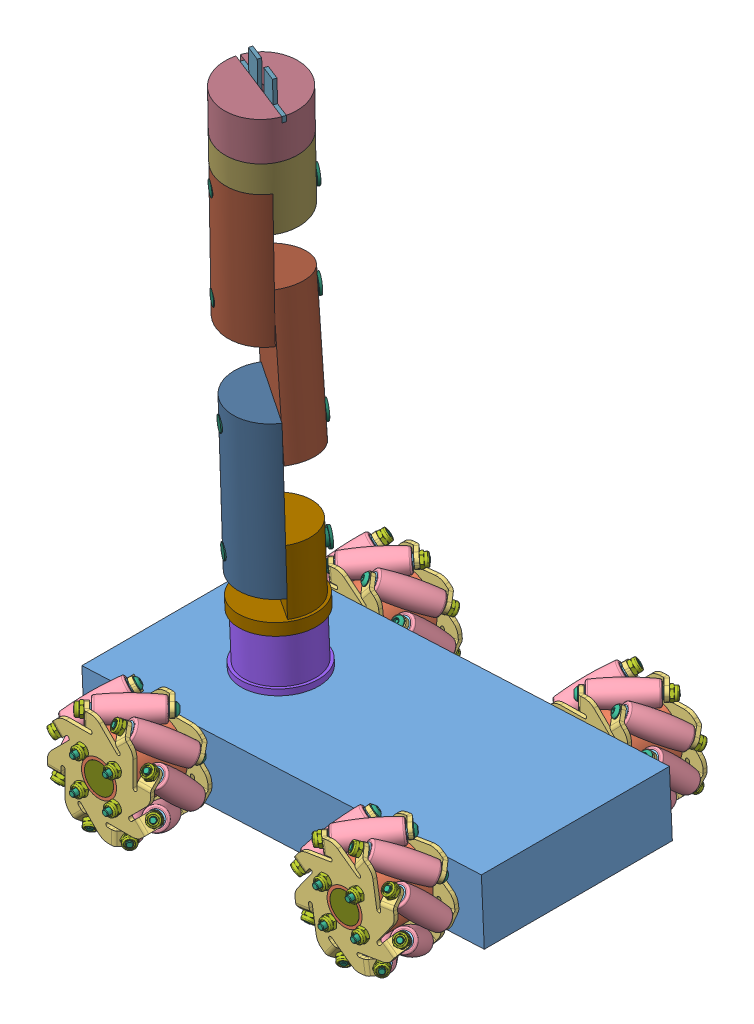
SolidWorks assembly bot assem, configuration Default. Lengths in mm.
Overall size (344.81 538.41 284.43).
226 component instances, 16 part files, 22 mates.
Components (placement in the parent):
- Part4-1: Part4 [Default] at (-50.0602 327.8462 218.6785) x (0.99893 0.046251 0) z (0 0 1) size (342.54 57 161.07)
- mecanum wheel assembly-2: mecanum wheel assembly [Default] at (-110.7954 326.5156 308.7657) size (102.2 102.2 64.43) (flexible)
  - 3.shaft-1: 3.shaft [Default] at (-45.6858 23.4322 30.452) size (53.34 53.34 52.51)
  - 1.frame-1: 1.frame [Default] at (-45.6858 23.4322 39.6232) x (-1 0 0) z (0 0 -1) size (91.71 91.71 12.64)
  - 1.frame-2: 1.frame [Default] at (-45.6858 23.4322 -6.2193) x (-1 0 0) z (0 0 1) size (91.71 91.71 12.64)
  - 2.roller-1: 2.roller [Default] at (-84.0268 23.5333 16.638) x (0 -0.707107 0.707107) z (0.983638 0.127391 0.127391) size (46.68 20 20)
  - 4.roller_bracket-1: 4.roller_bracket [Default] at (-84.0268 39.7299 0.4414) x (-0.383049 0.653174 0.653174) z (-0.923728 -0.270857 -0.270857) size (12.5 3.33 12.5)
  - 4.roller_bracket-2: 4.roller_bracket [Default] at (-84.0268 7.3367 32.8346) x (0.850043 -0.372442 -0.372442) z (-0.526713 -0.601071 -0.601071) size (12.5 3.33 12.5)
  - 5.bolt-2: 5.bolt [Default] at (-84.0268 36.2864 3.8849) x (0 -0.707107 0.707107) z (-0.604734 0.56316 0.56316) size (64.43 9.5 9.5)
  - torque nut 08_iso-1: torque nut 08_iso [ISO 10511-M6-N] at (-84.0268 1.8311 38.2658) x (1 0 0) z (0 -0.707107 0.707107) size (10 11.55 6)
  - 4.roller_bracket-3: 4.roller_bracket [Default] at (-84.3212 7.8452 0.4414) x (-0.732721 0.191007 0.653174) z (-0.46165 -0.844699 -0.270857) size (12.5 3.33 12.5)
  - 4.roller_bracket-4: 4.roller_bracket [Default] at (-61.9835 -14.9088 0.4414) x (-0.653174 -0.383049 0.653174) z (0.270857 -0.923728 -0.270857) size (12.5 3.33 12.5)
  - 4.roller_bracket-5: 4.roller_bracket [Default] at (-30.0988 -15.2032 0.4414) x (-0.191007 -0.732721 0.653174) z (0.844699 -0.46165 -0.270857) size (12.5 3.33 12.5)
  - 4.roller_bracket-6: 4.roller_bracket [Default] at (-7.3448 7.1345 0.4414) x (0.383049 -0.653174 0.653174) z (0.923728 0.270857 -0.270857) size (12.5 3.33 12.5)
  - 4.roller_bracket-7: 4.roller_bracket [Default] at (-7.0504 39.0192 0.4414) x (0.732721 -0.191007 0.653174) z (0.46165 0.844699 -0.270857) size (12.5 3.33 12.5)
  - 4.roller_bracket-8: 4.roller_bracket [Default] at (-29.3881 61.7732 0.4414) x (0.653174 0.383049 0.653174) z (-0.270857 0.923728 -0.270857) size (12.5 3.33 12.5)
  - 4.roller_bracket-9: 4.roller_bracket [Default] at (-61.2728 62.0676 0.4414) x (0.191007 0.732721 0.653174) z (-0.844699 0.46165 -0.270857) size (12.5 3.33 12.5)
  - 2.roller-2: 2.roller [Default] at (-72.8685 -3.6075 16.638) x (0.5 -0.5 0.707107) z (0.605458 0.785616 0.127391) size (46.68 20 20)
  - 2.roller-3: 2.roller [Default] at (-45.7869 -14.9088 16.638) x (0.707107 0 0.707107) z (-0.127391 0.983638 0.127391) size (46.68 20 20)
  - 2.roller-4: 2.roller [Default] at (-18.6461 -3.7505 16.638) x (0.5 0.5 0.707107) z (-0.785616 0.605458 0.127391) size (46.68 20 20)
  - 2.roller-5: 2.roller [Default] at (-7.3448 23.3311 16.638) x (0 0.707107 0.707107) z (-0.983638 -0.127391 0.127391) size (46.68 20 20)
  - 2.roller-6: 2.roller [Default] at (-18.5031 50.4719 16.638) x (-0.5 0.5 0.707107) z (-0.605458 -0.785616 0.127391) size (46.68 20 20)
  - 2.roller-7: 2.roller [Default] at (-45.5847 61.7732 16.638) x (-0.707107 0 0.707107) z (0.127391 -0.983638 0.127391) size (46.68 20 20)
  - 2.roller-8: 2.roller [Default] at (-72.7255 50.6149 16.638) x (-0.5 -0.5 0.707107) z (0.785616 -0.605458 0.127391) size (46.68 20 20)
  - 4.roller_bracket-10: 4.roller_bracket [Default] at (-61.4158 -15.0602 32.8346) x (0.864428 0.337715 -0.372442) z (0.052579 -0.797464 -0.601071) size (12.5 3.33 12.5)
  - 4.roller_bracket-11: 4.roller_bracket [Default] at (-29.5903 -14.9088 32.8346) x (0.372442 0.850043 -0.372442) z (0.601071 -0.526713 -0.601071) size (12.5 3.33 12.5)
  - 4.roller_bracket-12: 4.roller_bracket [Default] at (-7.1934 7.7022 32.8346) x (-0.337715 0.864428 -0.372442) z (0.797464 0.052579 -0.601071) size (12.5 3.33 12.5)
  - 4.roller_bracket-13: 4.roller_bracket [Default] at (-7.3448 39.5276 32.8346) x (-0.850043 0.372442 -0.372442) z (0.526713 0.601071 -0.601071) size (12.5 3.33 12.5)
  - 4.roller_bracket-14: 4.roller_bracket [Default] at (-29.9558 61.9246 32.8346) x (-0.864428 -0.337715 -0.372442) z (-0.052579 0.797464 -0.601071) size (12.5 3.33 12.5)
  - 4.roller_bracket-15: 4.roller_bracket [Default] at (-61.7812 61.7732 32.8346) x (-0.372442 -0.850043 -0.372442) z (-0.601071 0.526713 -0.601071) size (12.5 3.33 12.5)
  - 4.roller_bracket-16: 4.roller_bracket [Default] at (-84.1782 39.1622 32.8346) x (0.337715 -0.864428 -0.372442) z (-0.797464 -0.052579 -0.601071) size (12.5 3.33 12.5)
  - 5.bolt-3: 5.bolt [Default] at (-81.8863 5.4103 3.8849) x (0.5 -0.5 0.707107) z (-0.825825 -0.029397 0.56316) size (64.43 9.5 9.5)
  - 5.bolt-4: 5.bolt [Default] at (-58.54 -14.9088 3.8849) x (0.707107 0 0.707107) z (-0.56316 -0.604734 0.56316) size (64.43 9.5 9.5)
  - 5.bolt-5: 5.bolt [Default] at (-27.6639 -12.7683 3.8849) x (0.5 0.5 0.707107) z (0.029397 -0.825825 0.56316) size (64.43 9.5 9.5)
  - 5.bolt-6: 5.bolt [Default] at (-7.3448 10.578 3.8849) x (0 0.707107 0.707107) z (0.604734 -0.56316 0.56316) size (64.43 9.5 9.5)
  - 5.bolt-7: 5.bolt [Default] at (-9.4853 41.4541 3.8849) x (-0.5 0.5 0.707107) z (0.825825 0.029397 0.56316) size (64.43 9.5 9.5)
  - 5.bolt-8: 5.bolt [Default] at (-32.8316 61.7732 3.8849) x (-0.707107 0 0.707107) z (0.56316 0.604734 0.56316) size (64.43 9.5 9.5)
  - 5.bolt-9: 5.bolt [Default] at (-63.7077 59.6327 3.8849) x (-0.5 -0.5 0.707107) z (-0.029397 0.825825 0.56316) size (64.43 9.5 9.5)
  - torque nut 08_iso-2: torque nut 08_iso [ISO 10511-M6-N] at (-57.5227 -18.9532 38.2658) x (0.707107 0.707107 0) z (0.5 -0.5 0.707107) size (10 11.55 6)
  - torque nut 08_iso-3: torque nut 08_iso [ISO 10511-M6-N] at (-24.0847 -14.9088 38.2658) x (0 1 0) z (0.707107 0 0.707107) size (10 11.55 6)
  - torque nut 08_iso-4: torque nut 08_iso [ISO 10511-M6-N] at (-3.3004 11.5953 38.2658) x (-0.707107 0.707107 0) z (0.5 0.5 0.707107) size (10 11.55 6)
  - torque nut 08_iso-5: torque nut 08_iso [ISO 10511-M6-N] at (-7.3448 45.0332 38.2658) x (-1 0 0) z (0 0.707107 0.707107) size (10 11.55 6)
  - torque nut 08_iso-6: torque nut 08_iso [ISO 10511-M6-N] at (-33.8489 65.8176 38.2658) x (-0.707107 -0.707107 0) z (-0.5 0.5 0.707107) size (10 11.55 6)
  - torque nut 08_iso-7: torque nut 08_iso [ISO 10511-M6-N] at (-67.2868 61.7732 38.2658) x (0 -1 0) z (-0.707107 0 0.707107) size (10 11.55 6)
  - torque nut 08_iso-8: torque nut 08_iso [ISO 10511-M6-N] at (-88.0712 35.2691 38.2658) x (0.707107 -0.707107 0) z (-0.5 -0.5 0.707107) size (10 11.55 6)
  - 5.bolt-10: 5.bolt [Default] at (-31.5408 37.5772 -0.0834) x (0 0 1) z (-0.509821 0.86028 0) size (64.43 9.5 9.5)
  - torque nut 08_iso-9: torque nut 08_iso [ISO 10511-M6-N] at (-31.5408 37.5772 45.8572) x (0.993457 -0.114205 0) z (0 0 1) size (10 11.55 6)
  - 5.bolt-12: 5.bolt [Default] at (-59.8308 37.5772 -0.0834) x (0 0 1) z (-0.86028 -0.509821 0) size (64.43 9.5 9.5)
  - 5.bolt-13: 5.bolt [Default] at (-59.8308 9.2872 -0.0834) x (0 0 1) z (0.509821 -0.86028 0) size (64.43 9.5 9.5)
  - 5.bolt-14: 5.bolt [Default] at (-31.5408 9.2872 -0.0834) x (0 0 1) z (0.86028 0.509821 0) size (64.43 9.5 9.5)
  - torque nut 08_iso-11: torque nut 08_iso [ISO 10511-M6-N] at (-59.8308 37.5772 45.8572) x (0.114205 0.993457 0) z (0 0 1) size (10 11.55 6)
  - torque nut 08_iso-12: torque nut 08_iso [ISO 10511-M6-N] at (-59.8308 9.2872 45.8572) x (-0.993457 0.114205 0) z (0 0 1) size (10 11.55 6)
  - torque nut 08_iso-13: torque nut 08_iso [ISO 10511-M6-N] at (-31.5408 9.2872 45.8572) x (-0.114205 -0.993457 0) z (0 0 1) size (10 11.55 6)
- mecanum wheel assembly-3: mecanum wheel assembly [Default] at (102.6865 343.7947 308.7657) x (0.987351 0.158553 0) z (0 0 1) size (102.2 102.2 64.43) (flexible)
  - 3.shaft-1: 3.shaft [Default] at (-45.6858 23.4322 30.452) size (53.34 53.34 52.51)
  - 1.frame-1: 1.frame [Default] at (-45.6858 23.4322 39.6232) x (-1 0 0) z (0 0 -1) size (91.71 91.71 12.64)
  - 1.frame-2: 1.frame [Default] at (-45.6858 23.4322 -6.2193) x (-1 0 0) z (0 0 1) size (91.71 91.71 12.64)
  - 2.roller-1: 2.roller [Default] at (-84.0268 23.5333 16.638) x (0 -0.707107 0.707107) z (0.983638 0.127391 0.127391) size (46.68 20 20)
  - 4.roller_bracket-1: 4.roller_bracket [Default] at (-84.0268 39.7299 0.4414) x (-0.383049 0.653174 0.653174) z (-0.923728 -0.270857 -0.270857) size (12.5 3.33 12.5)
  - 4.roller_bracket-2: 4.roller_bracket [Default] at (-84.0268 7.3367 32.8346) x (0.850043 -0.372442 -0.372442) z (-0.526713 -0.601071 -0.601071) size (12.5 3.33 12.5)
  - 5.bolt-2: 5.bolt [Default] at (-84.0268 36.2864 3.8849) x (0 -0.707107 0.707107) z (-0.604734 0.56316 0.56316) size (64.43 9.5 9.5)
  - torque nut 08_iso-1: torque nut 08_iso [ISO 10511-M6-N] at (-84.0268 1.8311 38.2658) x (1 0 0) z (0 -0.707107 0.707107) size (10 11.55 6)
  - 4.roller_bracket-3: 4.roller_bracket [Default] at (-84.3212 7.8452 0.4414) x (-0.732721 0.191007 0.653174) z (-0.46165 -0.844699 -0.270857) size (12.5 3.33 12.5)
  - 4.roller_bracket-4: 4.roller_bracket [Default] at (-61.9835 -14.9088 0.4414) x (-0.653174 -0.383049 0.653174) z (0.270857 -0.923728 -0.270857) size (12.5 3.33 12.5)
  - 4.roller_bracket-5: 4.roller_bracket [Default] at (-30.0988 -15.2032 0.4414) x (-0.191007 -0.732721 0.653174) z (0.844699 -0.46165 -0.270857) size (12.5 3.33 12.5)
  - 4.roller_bracket-6: 4.roller_bracket [Default] at (-7.3448 7.1345 0.4414) x (0.383049 -0.653174 0.653174) z (0.923728 0.270857 -0.270857) size (12.5 3.33 12.5)
  - 4.roller_bracket-7: 4.roller_bracket [Default] at (-7.0504 39.0192 0.4414) x (0.732721 -0.191007 0.653174) z (0.46165 0.844699 -0.270857) size (12.5 3.33 12.5)
  - 4.roller_bracket-8: 4.roller_bracket [Default] at (-29.3881 61.7732 0.4414) x (0.653174 0.383049 0.653174) z (-0.270857 0.923728 -0.270857) size (12.5 3.33 12.5)
  - 4.roller_bracket-9: 4.roller_bracket [Default] at (-61.2728 62.0676 0.4414) x (0.191007 0.732721 0.653174) z (-0.844699 0.46165 -0.270857) size (12.5 3.33 12.5)
  - 2.roller-2: 2.roller [Default] at (-72.8685 -3.6075 16.638) x (0.5 -0.5 0.707107) z (0.605458 0.785616 0.127391) size (46.68 20 20)
  - 2.roller-3: 2.roller [Default] at (-45.7869 -14.9088 16.638) x (0.707107 0 0.707107) z (-0.127391 0.983638 0.127391) size (46.68 20 20)
  - 2.roller-4: 2.roller [Default] at (-18.6461 -3.7505 16.638) x (0.5 0.5 0.707107) z (-0.785616 0.605458 0.127391) size (46.68 20 20)
  - 2.roller-5: 2.roller [Default] at (-7.3448 23.3311 16.638) x (0 0.707107 0.707107) z (-0.983638 -0.127391 0.127391) size (46.68 20 20)
  - 2.roller-6: 2.roller [Default] at (-18.5031 50.4719 16.638) x (-0.5 0.5 0.707107) z (-0.605458 -0.785616 0.127391) size (46.68 20 20)
  - 2.roller-7: 2.roller [Default] at (-45.5847 61.7732 16.638) x (-0.707107 0 0.707107) z (0.127391 -0.983638 0.127391) size (46.68 20 20)
  - 2.roller-8: 2.roller [Default] at (-72.7255 50.6149 16.638) x (-0.5 -0.5 0.707107) z (0.785616 -0.605458 0.127391) size (46.68 20 20)
  - 4.roller_bracket-10: 4.roller_bracket [Default] at (-61.4158 -15.0602 32.8346) x (0.864428 0.337715 -0.372442) z (0.052579 -0.797464 -0.601071) size (12.5 3.33 12.5)
  - 4.roller_bracket-11: 4.roller_bracket [Default] at (-29.5903 -14.9088 32.8346) x (0.372442 0.850043 -0.372442) z (0.601071 -0.526713 -0.601071) size (12.5 3.33 12.5)
  - 4.roller_bracket-12: 4.roller_bracket [Default] at (-7.1934 7.7022 32.8346) x (-0.337715 0.864428 -0.372442) z (0.797464 0.052579 -0.601071) size (12.5 3.33 12.5)
  - 4.roller_bracket-13: 4.roller_bracket [Default] at (-7.3448 39.5276 32.8346) x (-0.850043 0.372442 -0.372442) z (0.526713 0.601071 -0.601071) size (12.5 3.33 12.5)
  - 4.roller_bracket-14: 4.roller_bracket [Default] at (-29.9558 61.9246 32.8346) x (-0.864428 -0.337715 -0.372442) z (-0.052579 0.797464 -0.601071) size (12.5 3.33 12.5)
  - 4.roller_bracket-15: 4.roller_bracket [Default] at (-61.7812 61.7732 32.8346) x (-0.372442 -0.850043 -0.372442) z (-0.601071 0.526713 -0.601071) size (12.5 3.33 12.5)
  - 4.roller_bracket-16: 4.roller_bracket [Default] at (-84.1782 39.1622 32.8346) x (0.337715 -0.864428 -0.372442) z (-0.797464 -0.052579 -0.601071) size (12.5 3.33 12.5)
  - 5.bolt-3: 5.bolt [Default] at (-81.8863 5.4103 3.8849) x (0.5 -0.5 0.707107) z (-0.825825 -0.029397 0.56316) size (64.43 9.5 9.5)
  - 5.bolt-4: 5.bolt [Default] at (-58.54 -14.9088 3.8849) x (0.707107 0 0.707107) z (-0.56316 -0.604734 0.56316) size (64.43 9.5 9.5)
  - 5.bolt-5: 5.bolt [Default] at (-27.6639 -12.7683 3.8849) x (0.5 0.5 0.707107) z (0.029397 -0.825825 0.56316) size (64.43 9.5 9.5)
  - 5.bolt-6: 5.bolt [Default] at (-7.3448 10.578 3.8849) x (0 0.707107 0.707107) z (0.604734 -0.56316 0.56316) size (64.43 9.5 9.5)
  - 5.bolt-7: 5.bolt [Default] at (-9.4853 41.4541 3.8849) x (-0.5 0.5 0.707107) z (0.825825 0.029397 0.56316) size (64.43 9.5 9.5)
  - 5.bolt-8: 5.bolt [Default] at (-32.8316 61.7732 3.8849) x (-0.707107 0 0.707107) z (0.56316 0.604734 0.56316) size (64.43 9.5 9.5)
  - 5.bolt-9: 5.bolt [Default] at (-63.7077 59.6327 3.8849) x (-0.5 -0.5 0.707107) z (-0.029397 0.825825 0.56316) size (64.43 9.5 9.5)
  - torque nut 08_iso-2: torque nut 08_iso [ISO 10511-M6-N] at (-57.5227 -18.9532 38.2658) x (0.707107 0.707107 0) z (0.5 -0.5 0.707107) size (10 11.55 6)
  - torque nut 08_iso-3: torque nut 08_iso [ISO 10511-M6-N] at (-24.0847 -14.9088 38.2658) x (0 1 0) z (0.707107 0 0.707107) size (10 11.55 6)
  - torque nut 08_iso-4: torque nut 08_iso [ISO 10511-M6-N] at (-3.3004 11.5953 38.2658) x (-0.707107 0.707107 0) z (0.5 0.5 0.707107) size (10 11.55 6)
  - torque nut 08_iso-5: torque nut 08_iso [ISO 10511-M6-N] at (-7.3448 45.0332 38.2658) x (-1 0 0) z (0 0.707107 0.707107) size (10 11.55 6)
  - torque nut 08_iso-6: torque nut 08_iso [ISO 10511-M6-N] at (-33.8489 65.8176 38.2658) x (-0.707107 -0.707107 0) z (-0.5 0.5 0.707107) size (10 11.55 6)
  - torque nut 08_iso-7: torque nut 08_iso [ISO 10511-M6-N] at (-67.2868 61.7732 38.2658) x (0 -1 0) z (-0.707107 0 0.707107) size (10 11.55 6)
  - torque nut 08_iso-8: torque nut 08_iso [ISO 10511-M6-N] at (-88.0712 35.2691 38.2658) x (0.707107 -0.707107 0) z (-0.5 -0.5 0.707107) size (10 11.55 6)
  - 5.bolt-10: 5.bolt [Default] at (-31.5408 37.5772 -0.0834) x (0 0 1) z (-0.509821 0.86028 0) size (64.43 9.5 9.5)
  - torque nut 08_iso-9: torque nut 08_iso [ISO 10511-M6-N] at (-31.5408 37.5772 45.8572) x (0.993457 -0.114205 0) z (0 0 1) size (10 11.55 6)
  - 5.bolt-12: 5.bolt [Default] at (-59.8308 37.5772 -0.0834) x (0 0 1) z (-0.86028 -0.509821 0) size (64.43 9.5 9.5)
  - 5.bolt-13: 5.bolt [Default] at (-59.8308 9.2872 -0.0834) x (0 0 1) z (0.509821 -0.86028 0) size (64.43 9.5 9.5)
  - 5.bolt-14: 5.bolt [Default] at (-31.5408 9.2872 -0.0834) x (0 0 1) z (0.86028 0.509821 0) size (64.43 9.5 9.5)
  - torque nut 08_iso-11: torque nut 08_iso [ISO 10511-M6-N] at (-59.8308 37.5772 45.8572) x (0.114205 0.993457 0) z (0 0 1) size (10 11.55 6)
  - torque nut 08_iso-12: torque nut 08_iso [ISO 10511-M6-N] at (-59.8308 9.2872 45.8572) x (-0.993457 0.114205 0) z (0 0 1) size (10 11.55 6)
  - torque nut 08_iso-13: torque nut 08_iso [ISO 10511-M6-N] at (-31.5408 9.2872 45.8572) x (-0.114205 -0.993457 0) z (0 0 1) size (10 11.55 6)
- mecanum wheel assembly-5: mecanum wheel assembly [Default] at (-113.5364 378.0903 128.5913) x (0.994367 0.105992 0) z (0 0 -1) size (102.2 102.2 64.43) (flexible)
  - 3.shaft-1: 3.shaft [Default] at (-45.6858 23.4322 30.452) size (53.34 53.34 52.51)
  - 1.frame-1: 1.frame [Default] at (-45.6858 23.4322 39.6232) x (-1 0 0) z (0 0 -1) size (91.71 91.71 12.64)
  - 1.frame-2: 1.frame [Default] at (-45.6858 23.4322 -6.2193) x (-1 0 0) z (0 0 1) size (91.71 91.71 12.64)
  - 2.roller-1: 2.roller [Default] at (-84.0268 23.5333 16.638) x (0 -0.707107 0.707107) z (0.983638 0.127391 0.127391) size (46.68 20 20)
  - 4.roller_bracket-1: 4.roller_bracket [Default] at (-84.0268 39.7299 0.4414) x (-0.383049 0.653174 0.653174) z (-0.923728 -0.270857 -0.270857) size (12.5 3.33 12.5)
  - 4.roller_bracket-2: 4.roller_bracket [Default] at (-84.0268 7.3367 32.8346) x (0.850043 -0.372442 -0.372442) z (-0.526713 -0.601071 -0.601071) size (12.5 3.33 12.5)
  - 5.bolt-2: 5.bolt [Default] at (-84.0268 36.2864 3.8849) x (0 -0.707107 0.707107) z (-0.604734 0.56316 0.56316) size (64.43 9.5 9.5)
  - torque nut 08_iso-1: torque nut 08_iso [ISO 10511-M6-N] at (-84.0268 1.8311 38.2658) x (1 0 0) z (0 -0.707107 0.707107) size (10 11.55 6)
  - 4.roller_bracket-3: 4.roller_bracket [Default] at (-84.3212 7.8452 0.4414) x (-0.732721 0.191007 0.653174) z (-0.46165 -0.844699 -0.270857) size (12.5 3.33 12.5)
  - 4.roller_bracket-4: 4.roller_bracket [Default] at (-61.9835 -14.9088 0.4414) x (-0.653174 -0.383049 0.653174) z (0.270857 -0.923728 -0.270857) size (12.5 3.33 12.5)
  - 4.roller_bracket-5: 4.roller_bracket [Default] at (-30.0988 -15.2032 0.4414) x (-0.191007 -0.732721 0.653174) z (0.844699 -0.46165 -0.270857) size (12.5 3.33 12.5)
  - 4.roller_bracket-6: 4.roller_bracket [Default] at (-7.3448 7.1345 0.4414) x (0.383049 -0.653174 0.653174) z (0.923728 0.270857 -0.270857) size (12.5 3.33 12.5)
  - 4.roller_bracket-7: 4.roller_bracket [Default] at (-7.0504 39.0192 0.4414) x (0.732721 -0.191007 0.653174) z (0.46165 0.844699 -0.270857) size (12.5 3.33 12.5)
  - 4.roller_bracket-8: 4.roller_bracket [Default] at (-29.3881 61.7732 0.4414) x (0.653174 0.383049 0.653174) z (-0.270857 0.923728 -0.270857) size (12.5 3.33 12.5)
  - 4.roller_bracket-9: 4.roller_bracket [Default] at (-61.2728 62.0676 0.4414) x (0.191007 0.732721 0.653174) z (-0.844699 0.46165 -0.270857) size (12.5 3.33 12.5)
  - 2.roller-2: 2.roller [Default] at (-72.8685 -3.6075 16.638) x (0.5 -0.5 0.707107) z (0.605458 0.785616 0.127391) size (46.68 20 20)
  - 2.roller-3: 2.roller [Default] at (-45.7869 -14.9088 16.638) x (0.707107 0 0.707107) z (-0.127391 0.983638 0.127391) size (46.68 20 20)
  - 2.roller-4: 2.roller [Default] at (-18.6461 -3.7505 16.638) x (0.5 0.5 0.707107) z (-0.785616 0.605458 0.127391) size (46.68 20 20)
  - 2.roller-5: 2.roller [Default] at (-7.3448 23.3311 16.638) x (0 0.707107 0.707107) z (-0.983638 -0.127391 0.127391) size (46.68 20 20)
  - 2.roller-6: 2.roller [Default] at (-18.5031 50.4719 16.638) x (-0.5 0.5 0.707107) z (-0.605458 -0.785616 0.127391) size (46.68 20 20)
  - 2.roller-7: 2.roller [Default] at (-45.5847 61.7732 16.638) x (-0.707107 0 0.707107) z (0.127391 -0.983638 0.127391) size (46.68 20 20)
  - 2.roller-8: 2.roller [Default] at (-72.7255 50.6149 16.638) x (-0.5 -0.5 0.707107) z (0.785616 -0.605458 0.127391) size (46.68 20 20)
  - 4.roller_bracket-10: 4.roller_bracket [Default] at (-61.4158 -15.0602 32.8346) x (0.864428 0.337715 -0.372442) z (0.052579 -0.797464 -0.601071) size (12.5 3.33 12.5)
  - 4.roller_bracket-11: 4.roller_bracket [Default] at (-29.5903 -14.9088 32.8346) x (0.372442 0.850043 -0.372442) z (0.601071 -0.526713 -0.601071) size (12.5 3.33 12.5)
  - 4.roller_bracket-12: 4.roller_bracket [Default] at (-7.1934 7.7022 32.8346) x (-0.337715 0.864428 -0.372442) z (0.797464 0.052579 -0.601071) size (12.5 3.33 12.5)
  - 4.roller_bracket-13: 4.roller_bracket [Default] at (-7.3448 39.5276 32.8346) x (-0.850043 0.372442 -0.372442) z (0.526713 0.601071 -0.601071) size (12.5 3.33 12.5)
  - 4.roller_bracket-14: 4.roller_bracket [Default] at (-29.9558 61.9246 32.8346) x (-0.864428 -0.337715 -0.372442) z (-0.052579 0.797464 -0.601071) size (12.5 3.33 12.5)
  - 4.roller_bracket-15: 4.roller_bracket [Default] at (-61.7812 61.7732 32.8346) x (-0.372442 -0.850043 -0.372442) z (-0.601071 0.526713 -0.601071) size (12.5 3.33 12.5)
  - 4.roller_bracket-16: 4.roller_bracket [Default] at (-84.1782 39.1622 32.8346) x (0.337715 -0.864428 -0.372442) z (-0.797464 -0.052579 -0.601071) size (12.5 3.33 12.5)
  - 5.bolt-3: 5.bolt [Default] at (-81.8863 5.4103 3.8849) x (0.5 -0.5 0.707107) z (-0.825825 -0.029397 0.56316) size (64.43 9.5 9.5)
  - 5.bolt-4: 5.bolt [Default] at (-58.54 -14.9088 3.8849) x (0.707107 0 0.707107) z (-0.56316 -0.604734 0.56316) size (64.43 9.5 9.5)
  - 5.bolt-5: 5.bolt [Default] at (-27.6639 -12.7683 3.8849) x (0.5 0.5 0.707107) z (0.029397 -0.825825 0.56316) size (64.43 9.5 9.5)
  - 5.bolt-6: 5.bolt [Default] at (-7.3448 10.578 3.8849) x (0 0.707107 0.707107) z (0.604734 -0.56316 0.56316) size (64.43 9.5 9.5)
  - 5.bolt-7: 5.bolt [Default] at (-9.4853 41.4541 3.8849) x (-0.5 0.5 0.707107) z (0.825825 0.029397 0.56316) size (64.43 9.5 9.5)
  - 5.bolt-8: 5.bolt [Default] at (-32.8316 61.7732 3.8849) x (-0.707107 0 0.707107) z (0.56316 0.604734 0.56316) size (64.43 9.5 9.5)
  - 5.bolt-9: 5.bolt [Default] at (-63.7077 59.6327 3.8849) x (-0.5 -0.5 0.707107) z (-0.029397 0.825825 0.56316) size (64.43 9.5 9.5)
  - torque nut 08_iso-2: torque nut 08_iso [ISO 10511-M6-N] at (-57.5227 -18.9532 38.2658) x (0.707107 0.707107 0) z (0.5 -0.5 0.707107) size (10 11.55 6)
  - torque nut 08_iso-3: torque nut 08_iso [ISO 10511-M6-N] at (-24.0847 -14.9088 38.2658) x (0 1 0) z (0.707107 0 0.707107) size (10 11.55 6)
  - torque nut 08_iso-4: torque nut 08_iso [ISO 10511-M6-N] at (-3.3004 11.5953 38.2658) x (-0.707107 0.707107 0) z (0.5 0.5 0.707107) size (10 11.55 6)
  - torque nut 08_iso-5: torque nut 08_iso [ISO 10511-M6-N] at (-7.3448 45.0332 38.2658) x (-1 0 0) z (0 0.707107 0.707107) size (10 11.55 6)
  - torque nut 08_iso-6: torque nut 08_iso [ISO 10511-M6-N] at (-33.8489 65.8176 38.2658) x (-0.707107 -0.707107 0) z (-0.5 0.5 0.707107) size (10 11.55 6)
  - torque nut 08_iso-7: torque nut 08_iso [ISO 10511-M6-N] at (-67.2868 61.7732 38.2658) x (0 -1 0) z (-0.707107 0 0.707107) size (10 11.55 6)
  - torque nut 08_iso-8: torque nut 08_iso [ISO 10511-M6-N] at (-88.0712 35.2691 38.2658) x (0.707107 -0.707107 0) z (-0.5 -0.5 0.707107) size (10 11.55 6)
  - 5.bolt-10: 5.bolt [Default] at (-31.5408 37.5772 -0.0834) x (0 0 1) z (-0.509821 0.86028 0) size (64.43 9.5 9.5)
  - torque nut 08_iso-9: torque nut 08_iso [ISO 10511-M6-N] at (-31.5408 37.5772 45.8572) x (0.993457 -0.114205 0) z (0 0 1) size (10 11.55 6)
  - 5.bolt-12: 5.bolt [Default] at (-59.8308 37.5772 -0.0834) x (0 0 1) z (-0.86028 -0.509821 0) size (64.43 9.5 9.5)
  - 5.bolt-13: 5.bolt [Default] at (-59.8308 9.2872 -0.0834) x (0 0 1) z (0.509821 -0.86028 0) size (64.43 9.5 9.5)
  - 5.bolt-14: 5.bolt [Default] at (-31.5408 9.2872 -0.0834) x (0 0 1) z (0.86028 0.509821 0) size (64.43 9.5 9.5)
  - torque nut 08_iso-11: torque nut 08_iso [ISO 10511-M6-N] at (-59.8308 37.5772 45.8572) x (0.114205 0.993457 0) z (0 0 1) size (10 11.55 6)
  - torque nut 08_iso-12: torque nut 08_iso [ISO 10511-M6-N] at (-59.8308 9.2872 45.8572) x (-0.993457 0.114205 0) z (0 0 1) size (10 11.55 6)
  - torque nut 08_iso-13: torque nut 08_iso [ISO 10511-M6-N] at (-31.5408 9.2872 45.8572) x (-0.114205 -0.993457 0) z (0 0 1) size (10 11.55 6)
- mecanum wheel assembly-7: mecanum wheel assembly [Default] at (99.2444 383.7039 128.5913) x (0.999918 0.012843 0) z (0 0 -1) size (102.2 102.2 64.43) (flexible)
  - 3.shaft-1: 3.shaft [Default] at (-45.6858 23.4322 30.452) size (53.34 53.34 52.51)
  - 1.frame-1: 1.frame [Default] at (-45.6858 23.4322 39.6232) x (-1 0 0) z (0 0 -1) size (91.71 91.71 12.64)
  - 1.frame-2: 1.frame [Default] at (-45.6858 23.4322 -6.2193) x (-1 0 0) z (0 0 1) size (91.71 91.71 12.64)
  - 2.roller-1: 2.roller [Default] at (-84.0268 23.5333 16.638) x (0 -0.707107 0.707107) z (0.983638 0.127391 0.127391) size (46.68 20 20)
  - 4.roller_bracket-1: 4.roller_bracket [Default] at (-84.0268 39.7299 0.4414) x (-0.383049 0.653174 0.653174) z (-0.923728 -0.270857 -0.270857) size (12.5 3.33 12.5)
  - 4.roller_bracket-2: 4.roller_bracket [Default] at (-84.0268 7.3367 32.8346) x (0.850043 -0.372442 -0.372442) z (-0.526713 -0.601071 -0.601071) size (12.5 3.33 12.5)
  - 5.bolt-2: 5.bolt [Default] at (-84.0268 36.2864 3.8849) x (0 -0.707107 0.707107) z (-0.604734 0.56316 0.56316) size (64.43 9.5 9.5)
  - torque nut 08_iso-1: torque nut 08_iso [ISO 10511-M6-N] at (-84.0268 1.8311 38.2658) x (1 0 0) z (0 -0.707107 0.707107) size (10 11.55 6)
  - 4.roller_bracket-3: 4.roller_bracket [Default] at (-84.3212 7.8452 0.4414) x (-0.732721 0.191007 0.653174) z (-0.46165 -0.844699 -0.270857) size (12.5 3.33 12.5)
  - 4.roller_bracket-4: 4.roller_bracket [Default] at (-61.9835 -14.9088 0.4414) x (-0.653174 -0.383049 0.653174) z (0.270857 -0.923728 -0.270857) size (12.5 3.33 12.5)
  - 4.roller_bracket-5: 4.roller_bracket [Default] at (-30.0988 -15.2032 0.4414) x (-0.191007 -0.732721 0.653174) z (0.844699 -0.46165 -0.270857) size (12.5 3.33 12.5)
  - 4.roller_bracket-6: 4.roller_bracket [Default] at (-7.3448 7.1345 0.4414) x (0.383049 -0.653174 0.653174) z (0.923728 0.270857 -0.270857) size (12.5 3.33 12.5)
  - 4.roller_bracket-7: 4.roller_bracket [Default] at (-7.0504 39.0192 0.4414) x (0.732721 -0.191007 0.653174) z (0.46165 0.844699 -0.270857) size (12.5 3.33 12.5)
  - 4.roller_bracket-8: 4.roller_bracket [Default] at (-29.3881 61.7732 0.4414) x (0.653174 0.383049 0.653174) z (-0.270857 0.923728 -0.270857) size (12.5 3.33 12.5)
  - 4.roller_bracket-9: 4.roller_bracket [Default] at (-61.2728 62.0676 0.4414) x (0.191007 0.732721 0.653174) z (-0.844699 0.46165 -0.270857) size (12.5 3.33 12.5)
  - 2.roller-2: 2.roller [Default] at (-72.8685 -3.6075 16.638) x (0.5 -0.5 0.707107) z (0.605458 0.785616 0.127391) size (46.68 20 20)
  - 2.roller-3: 2.roller [Default] at (-45.7869 -14.9088 16.638) x (0.707107 0 0.707107) z (-0.127391 0.983638 0.127391) size (46.68 20 20)
  - 2.roller-4: 2.roller [Default] at (-18.6461 -3.7505 16.638) x (0.5 0.5 0.707107) z (-0.785616 0.605458 0.127391) size (46.68 20 20)
  - 2.roller-5: 2.roller [Default] at (-7.3448 23.3311 16.638) x (0 0.707107 0.707107) z (-0.983638 -0.127391 0.127391) size (46.68 20 20)
  - 2.roller-6: 2.roller [Default] at (-18.5031 50.4719 16.638) x (-0.5 0.5 0.707107) z (-0.605458 -0.785616 0.127391) size (46.68 20 20)
  - 2.roller-7: 2.roller [Default] at (-45.5847 61.7732 16.638) x (-0.707107 0 0.707107) z (0.127391 -0.983638 0.127391) size (46.68 20 20)
  - 2.roller-8: 2.roller [Default] at (-72.7255 50.6149 16.638) x (-0.5 -0.5 0.707107) z (0.785616 -0.605458 0.127391) size (46.68 20 20)
  - 4.roller_bracket-10: 4.roller_bracket [Default] at (-61.4158 -15.0602 32.8346) x (0.864428 0.337715 -0.372442) z (0.052579 -0.797464 -0.601071) size (12.5 3.33 12.5)
  - 4.roller_bracket-11: 4.roller_bracket [Default] at (-29.5903 -14.9088 32.8346) x (0.372442 0.850043 -0.372442) z (0.601071 -0.526713 -0.601071) size (12.5 3.33 12.5)
  - 4.roller_bracket-12: 4.roller_bracket [Default] at (-7.1934 7.7022 32.8346) x (-0.337715 0.864428 -0.372442) z (0.797464 0.052579 -0.601071) size (12.5 3.33 12.5)
  - 4.roller_bracket-13: 4.roller_bracket [Default] at (-7.3448 39.5276 32.8346) x (-0.850043 0.372442 -0.372442) z (0.526713 0.601071 -0.601071) size (12.5 3.33 12.5)
  - 4.roller_bracket-14: 4.roller_bracket [Default] at (-29.9558 61.9246 32.8346) x (-0.864428 -0.337715 -0.372442) z (-0.052579 0.797464 -0.601071) size (12.5 3.33 12.5)
  - 4.roller_bracket-15: 4.roller_bracket [Default] at (-61.7812 61.7732 32.8346) x (-0.372442 -0.850043 -0.372442) z (-0.601071 0.526713 -0.601071) size (12.5 3.33 12.5)
  - 4.roller_bracket-16: 4.roller_bracket [Default] at (-84.1782 39.1622 32.8346) x (0.337715 -0.864428 -0.372442) z (-0.797464 -0.052579 -0.601071) size (12.5 3.33 12.5)
  - 5.bolt-3: 5.bolt [Default] at (-81.8863 5.4103 3.8849) x (0.5 -0.5 0.707107) z (-0.825825 -0.029397 0.56316) size (64.43 9.5 9.5)
  - 5.bolt-4: 5.bolt [Default] at (-58.54 -14.9088 3.8849) x (0.707107 0 0.707107) z (-0.56316 -0.604734 0.56316) size (64.43 9.5 9.5)
  - 5.bolt-5: 5.bolt [Default] at (-27.6639 -12.7683 3.8849) x (0.5 0.5 0.707107) z (0.029397 -0.825825 0.56316) size (64.43 9.5 9.5)
  - 5.bolt-6: 5.bolt [Default] at (-7.3448 10.578 3.8849) x (0 0.707107 0.707107) z (0.604734 -0.56316 0.56316) size (64.43 9.5 9.5)
  - 5.bolt-7: 5.bolt [Default] at (-9.4853 41.4541 3.8849) x (-0.5 0.5 0.707107) z (0.825825 0.029397 0.56316) size (64.43 9.5 9.5)
  - 5.bolt-8: 5.bolt [Default] at (-32.8316 61.7732 3.8849) x (-0.707107 0 0.707107) z (0.56316 0.604734 0.56316) size (64.43 9.5 9.5)
  - 5.bolt-9: 5.bolt [Default] at (-63.7077 59.6327 3.8849) x (-0.5 -0.5 0.707107) z (-0.029397 0.825825 0.56316) size (64.43 9.5 9.5)
  - torque nut 08_iso-2: torque nut 08_iso [ISO 10511-M6-N] at (-57.5227 -18.9532 38.2658) x (0.707107 0.707107 0) z (0.5 -0.5 0.707107) size (10 11.55 6)
  - torque nut 08_iso-3: torque nut 08_iso [ISO 10511-M6-N] at (-24.0847 -14.9088 38.2658) x (0 1 0) z (0.707107 0 0.707107) size (10 11.55 6)
  - torque nut 08_iso-4: torque nut 08_iso [ISO 10511-M6-N] at (-3.3004 11.5953 38.2658) x (-0.707107 0.707107 0) z (0.5 0.5 0.707107) size (10 11.55 6)
  - torque nut 08_iso-5: torque nut 08_iso [ISO 10511-M6-N] at (-7.3448 45.0332 38.2658) x (-1 0 0) z (0 0.707107 0.707107) size (10 11.55 6)
  - torque nut 08_iso-6: torque nut 08_iso [ISO 10511-M6-N] at (-33.8489 65.8176 38.2658) x (-0.707107 -0.707107 0) z (-0.5 0.5 0.707107) size (10 11.55 6)
  - torque nut 08_iso-7: torque nut 08_iso [ISO 10511-M6-N] at (-67.2868 61.7732 38.2658) x (0 -1 0) z (-0.707107 0 0.707107) size (10 11.55 6)
  - torque nut 08_iso-8: torque nut 08_iso [ISO 10511-M6-N] at (-88.0712 35.2691 38.2658) x (0.707107 -0.707107 0) z (-0.5 -0.5 0.707107) size (10 11.55 6)
  - 5.bolt-10: 5.bolt [Default] at (-31.5408 37.5772 -0.0834) x (0 0 1) z (-0.509821 0.86028 0) size (64.43 9.5 9.5)
  - torque nut 08_iso-9: torque nut 08_iso [ISO 10511-M6-N] at (-31.5408 37.5772 45.8572) x (0.993457 -0.114205 0) z (0 0 1) size (10 11.55 6)
  - 5.bolt-12: 5.bolt [Default] at (-59.8308 37.5772 -0.0834) x (0 0 1) z (-0.86028 -0.509821 0) size (64.43 9.5 9.5)
  - 5.bolt-13: 5.bolt [Default] at (-59.8308 9.2872 -0.0834) x (0 0 1) z (0.509821 -0.86028 0) size (64.43 9.5 9.5)
  - 5.bolt-14: 5.bolt [Default] at (-31.5408 9.2872 -0.0834) x (0 0 1) z (0.86028 0.509821 0) size (64.43 9.5 9.5)
  - torque nut 08_iso-11: torque nut 08_iso [ISO 10511-M6-N] at (-59.8308 37.5772 45.8572) x (0.114205 0.993457 0) z (0 0 1) size (10 11.55 6)
  - torque nut 08_iso-12: torque nut 08_iso [ISO 10511-M6-N] at (-59.8308 9.2872 45.8572) x (-0.993457 0.114205 0) z (0 0 1) size (10 11.55 6)
  - torque nut 08_iso-13: torque nut 08_iso [ISO 10511-M6-N] at (-31.5408 9.2872 45.8572) x (-0.114205 -0.993457 0) z (0 0 1) size (10 11.55 6)
- arm assem-2: arm assem [Default] at (-164.0861 361.5635 189.6567) x (0.99893 0.046251 0) z (0 0 1) size (102.36 450.82 98.34) (flexible)
  - 1.base-1: 1.base [Default] at (31.0727 15.045 29.0218) x (-1 0 0) z (0 0 1) size (65 43.19 65)
  - link1-2: link1 [Default] at (31.0727 58.235 29.0218) x (-0.830749 0 -0.556647) z (-0.556647 0 0.830749) size (65 65.59 65)
  - link 2-3: link 2 [Default] at (30.3905 85.8409 28.5646) x (-0.556647 0 0.830749) z (0.829884 -0.045625 0.556067) size (32.5 131.37 65)
  - link 3-3: link 3 [Default] at (24.4867 299.7261 24.6088) x (-0.556647 0 0.830749) z (-0.824633 -0.121126 -0.552548) size (32.5 119.38 65)
  - link 3-4: link 3 [Default] at (34.7812 384.7834 31.5066) x (0.556647 0 -0.830749) z (0.82631 -0.103245 0.553672) size (32.5 119.38 65)
  - link4-4: link4 [Default] at (36.8397 408.6551 32.8859) x (-0.82631 0.103245 -0.553672) z (-0.556647 0 0.830749) size (65 57.79 65)
  - gripper assem-1: gripper assem [Default] at (-2.666 419.7032 33.2245) x (-0.937026 0.100134 -0.334598) z (0.338564 0.025153 -0.940607) size (65 54.79 65) (flexible)
    - gripper head-1: gripper head [Default] at (-38.0108 -7.62 13.4158) size (65 34.79 65)
    - gripper jaw-1: gripper jaw [Default] at (-57.98 22.173 13.4158) size (25 25 3)
    - gripper jaw-2: gripper jaw [Default] at (-23.7863 22.173 13.4158) x (-1 0 0) z (0 0 -1) size (25 25 3)
- bolt-1: bolt [Default] at (-118.9428 467.5871 190.433) x (-0.556051 -0.025745 0.830749) z (0.831111 -0.00782 0.556051) size (67 15 15)
- bolt-2: bolt [Default] at (-119.7382 562.9267 192.8553) x (-0.556051 -0.025745 0.830749) z (0.830177 0.031093 0.556632) size (67 15 15)
- bolt-4: bolt [Default] at (-131.9771 647.3035 186.6763) x (-0.556051 -0.025745 0.830749) z (0.828614 0.060828 0.556507) size (67 15 15)
- bolt-6: bolt [Default] at (-128.5856 732.5768 191.5891) x (-0.556051 -0.025745 0.830749) z (0.827167 0.080573 0.55615) size (67 15 15)
- axle-2: axle [Default] at (53.8633 359.6868 351.7341) x (0 0 -1) z (1 0 0) size (266.1 25 25)
- axle-3: axle [Default] at (-156.4812 349.9478 351.7341) x (0 0 -1) z (0.987351 0.158553 0) size (266.1 25 25)
Mates (geometry in assembly coordinates):
- Concentric1: concentric anti-aligned: cylinder of Part4-1 through (-156.4812 349.9478 478.1646) axis (0 0 -1) radius 9; cylinder of mecanum wheel assembly-2/3.shaft-1 through (-156.4812 349.9478 302.5464) axis (0 0 1) radius 12.5025
- Coincident1: coincident anti-aligned: plane of Part4-1 through (-223.6462 373.8669 299.2124) normal (0 0 1); plane of mecanum wheel assembly-2/3.shaft-1 through (-156.4812 349.9478 299.2124) normal (0 0 -1)
- Concentric2: concentric anti-aligned: cylinder of Part4-1 through (53.8633 359.6868 478.1646) axis (0 0 -1) radius 9; cylinder of mecanum wheel assembly-3/3.shaft-1 through (53.8633 359.6868 302.5464) axis (0 0 1) radius 12.5025
- Coincident2: coincident anti-aligned: plane of Part4-1 through (-223.6462 373.8669 299.2124) normal (0 0 1); plane of mecanum wheel assembly-3/3.shaft-1 through (53.8633 359.6868 299.2124) normal (0 0 -1)
- Concentric3: concentric aligned: cylinder of Part4-1 through (-156.4812 349.9478 478.1646) axis (0 0 -1) radius 9; cylinder of mecanum wheel assembly-5/3.shaft-1 through (-156.4812 349.9478 134.8106) axis (0 0 -1) radius 12.5025
- Coincident3: coincident anti-aligned: plane of Part4-1 through (-223.6462 373.8669 138.1446) normal (0 0 -1); plane of mecanum wheel assembly-5/3.shaft-1 through (-156.4812 349.9478 138.1446) normal (0 0 1)
- Concentric4: concentric aligned: cylinder of Part4-1 through (53.8633 359.6868 478.1646) axis (0 0 -1) radius 9; cylinder of mecanum wheel assembly-7/3.shaft-1 through (53.8633 359.6868 134.8106) axis (0 0 -1) radius 12.5025
- Coincident4: coincident anti-aligned: plane of Part4-1 through (-223.6462 373.8669 138.1446) normal (0 0 -1); plane of mecanum wheel assembly-7/3.shaft-1 through (53.8633 359.6868 138.1446) normal (0 0 1)
- Concentric6: concentric anti-aligned: circle of Part4-1; circle of arm assem-2/1.base-1
- Coincident6: coincident anti-aligned: plane of Part4-1 through (-52.5577 381.7884 218.6785) normal (-0.046251 0.99893 0); plane of arm assem-2/1.base-1 through (-133.7425 378.0295 218.6785) normal (0.046251 -0.99893 0)
- Concentric7: concentric anti-aligned: cylinder of arm assem-2/link1-2 through (-112.8262 467.8703 181.2948) axis (-0.556051 -0.025745 0.830749) radius 6; cylinder of bolt-1 through (-156.1982 465.8621 246.0932) axis (0.556051 0.025745 -0.830749) radius 6
- Distance1: distance = 32 mm: plane of bolt-1 through (-120.0549 467.5356 192.0945) normal (-0.556051 -0.025745 0.830749); cylinder of arm assem-2/link1-2 through (-138.681 484.6925 218.6785) axis (0.046251 -0.99893 0) radius 30
- Concentric8: concentric anti-aligned: cylinder of arm assem-2/link 3-3 through (-107.5051 563.4931 174.5788) axis (-0.556051 -0.025745 0.830749) radius 6; cylinder of bolt-2 through (-156.9936 561.2017 248.5155) axis (0.556051 0.025745 -0.830749) radius 6
- Distance2: distance = 32 mm: plane of bolt-2 through (-120.8503 562.8752 194.5168) normal (-0.556051 -0.025745 0.830749); cylinder of arm assem-2/link 3-3 through (-136.0082 544.2868 222.3144) axis (-0.146428 0.986921 -0.067424) radius 32.5
- Concentric9: concentric anti-aligned: cylinder of arm assem-2/link 3-3 through (-120.022 647.8571 168.8152) axis (-0.556051 -0.025745 0.830749) radius 6; cylinder of bolt-4 through (-169.2325 645.5786 242.3365) axis (0.556051 0.025745 -0.830749) radius 6
- Distance3: distance = 32.5 mm: plane of bolt-4 through (-133.0892 647.252 188.3378) normal (-0.556051 -0.025745 0.830749); cylinder of arm assem-2/link 3-3 through (-136.0082 544.2868 222.3144) axis (-0.146428 0.986921 -0.067424) radius 32.5
- Concentric10: concentric anti-aligned: cylinder of arm assem-2/link4-4 through (-122.191 732.8729 182.0355) axis (-0.556051 -0.025745 0.830749) radius 6; cylinder of bolt-6 through (-165.841 730.8519 247.2493) axis (0.556051 0.025745 -0.830749) radius 6
- Distance4: distance = 32.5 mm: plane of bolt-6 through (-129.6977 732.5253 193.2506) normal (-0.556051 -0.025745 0.830749); cylinder of arm assem-2/link4-4 through (-148.3999 715.8334 219.3365) axis (0.039675 0.997558 0.057471) radius 32.5
- Concentric12: concentric aligned: cylinder of mecanum wheel assembly-7/3.shaft-1 through (53.8633 359.6868 134.8106) axis (0 0 -1) radius 12.5025; cylinder of axle-2 through (53.8633 359.6868 113.1341) axis (0 0 -1) radius 12.5
- Coincident8: coincident aligned: plane of mecanum wheel assembly-7/3.shaft-1 through (53.8633 359.6868 85.6341) normal (0 0 -1); plane of axle-2 through (53.8633 359.6868 85.6341) normal (0 0 -1)
- Concentric13: concentric aligned: cylinder of mecanum wheel assembly-5/3.shaft-1 through (-156.4812 349.9478 134.8106) axis (0 0 -1) radius 12.5025; cylinder of axle-3 through (-156.4812 349.9478 113.1341) axis (0 0 -1) radius 12.5
- Coincident9: coincident aligned: plane of mecanum wheel assembly-5/3.shaft-1 through (-156.4812 349.9478 85.6341) normal (0 0 -1); plane of axle-3 through (-156.4812 349.9478 85.6341) normal (0 0 -1)
